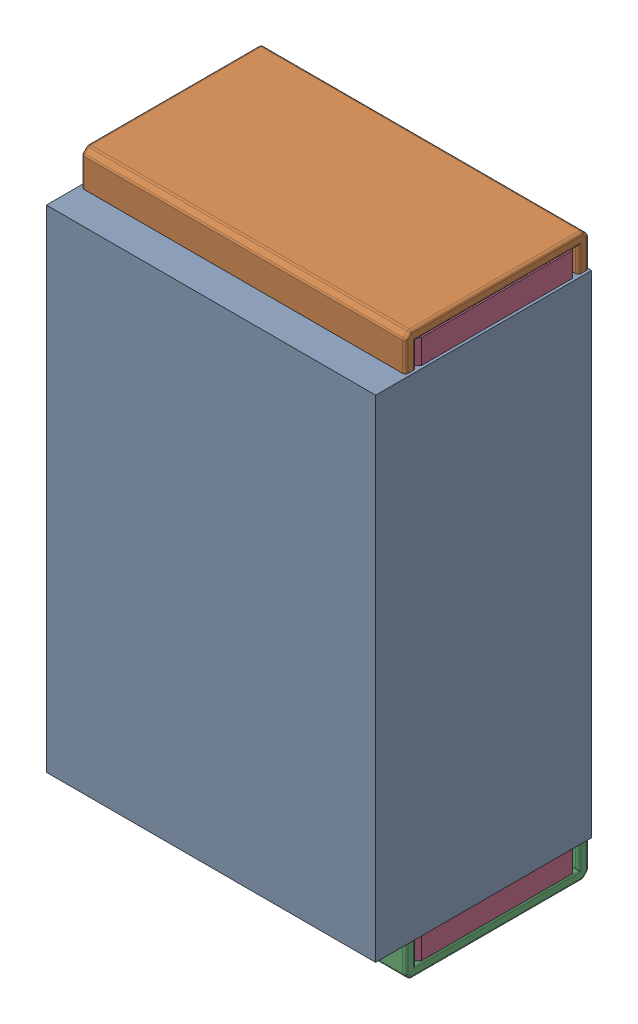
SolidWorks assembly R14, configuration Default. Lengths in mm.
Overall size (0.61 1.04 0.4).
3 component instances, 2 part files, 0 mates.
Components (placement in the parent):
- 1088881848-1: 1088881848 [Default] at (7.275 20.875 0) size (0.61 0.91 0.4)
  - Extruded-1-1: Extruded-1 [Default] at origin size (0.61 0.91 0.4)
- R0402-1: R0402 [Default] at (7.2749 20.875 0) x (0 1 0) z (1 0 0) size (1.04 0.34 0.6)
